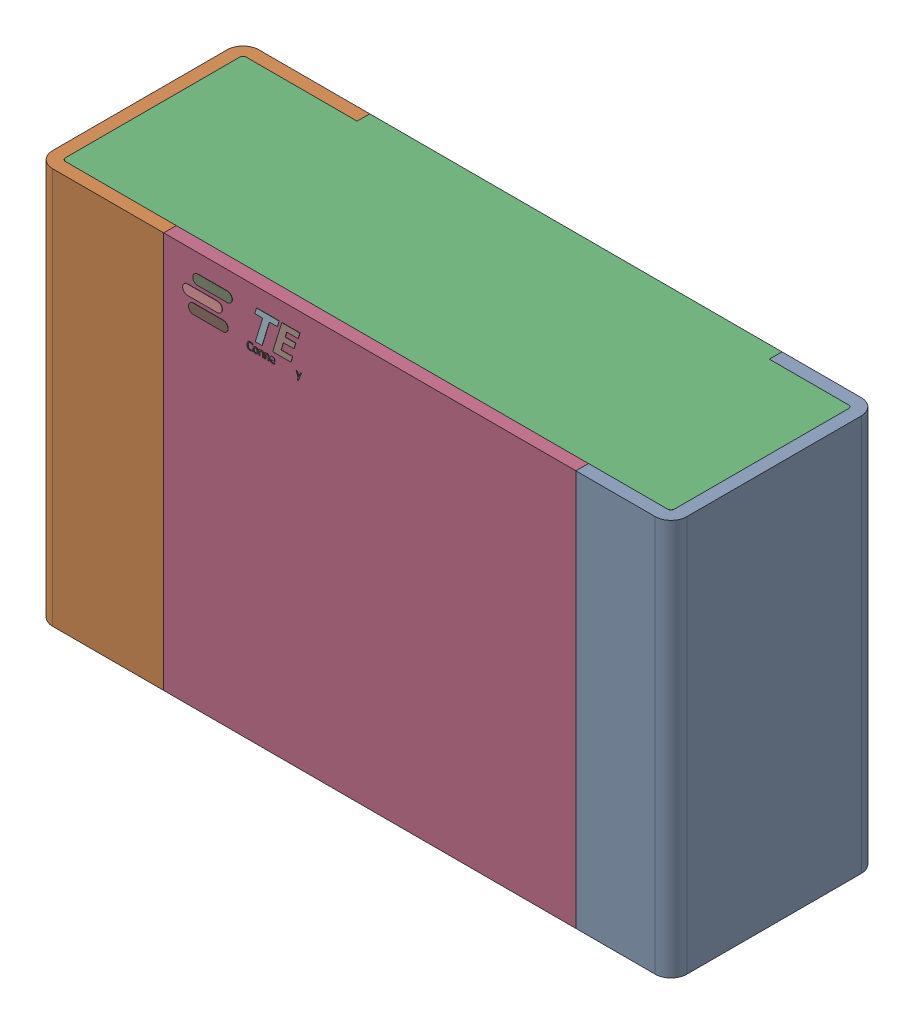
SolidWorks assembly R13.step, configuration Default. Lengths in mm.
Overall size (2 1.25 0.65).
5 component instances, 4 part files, 0 mates.
Components (placement in the parent):
- Res_TE_Connectivity_CPF0805B66R5E1_eec.step-1: Res_TE_Connectivity_CPF0805B66R5E1_eec.step [Default] at (37.973 53.948 0) x (1 0 0) z (0 0 1) size (2 1.25 0.65)
  - 1.step-1: 1.step [Default] at origin size (2 1.25 0.65)
  - 2.step-1: 2.step [Default] at origin size (1.92 1.25 0.61)
  - 3.step-1: 3.step [Default] at origin size (1.3 1.25 0.04)
  - TE connectivity Logo 1 (2).step-1: TE connectivity Logo 1 (2).step [Default] at (5.4285 0.313 0.551) x (-1 0 0) z (0 0 1) size (0.37 0.13 0.11)
